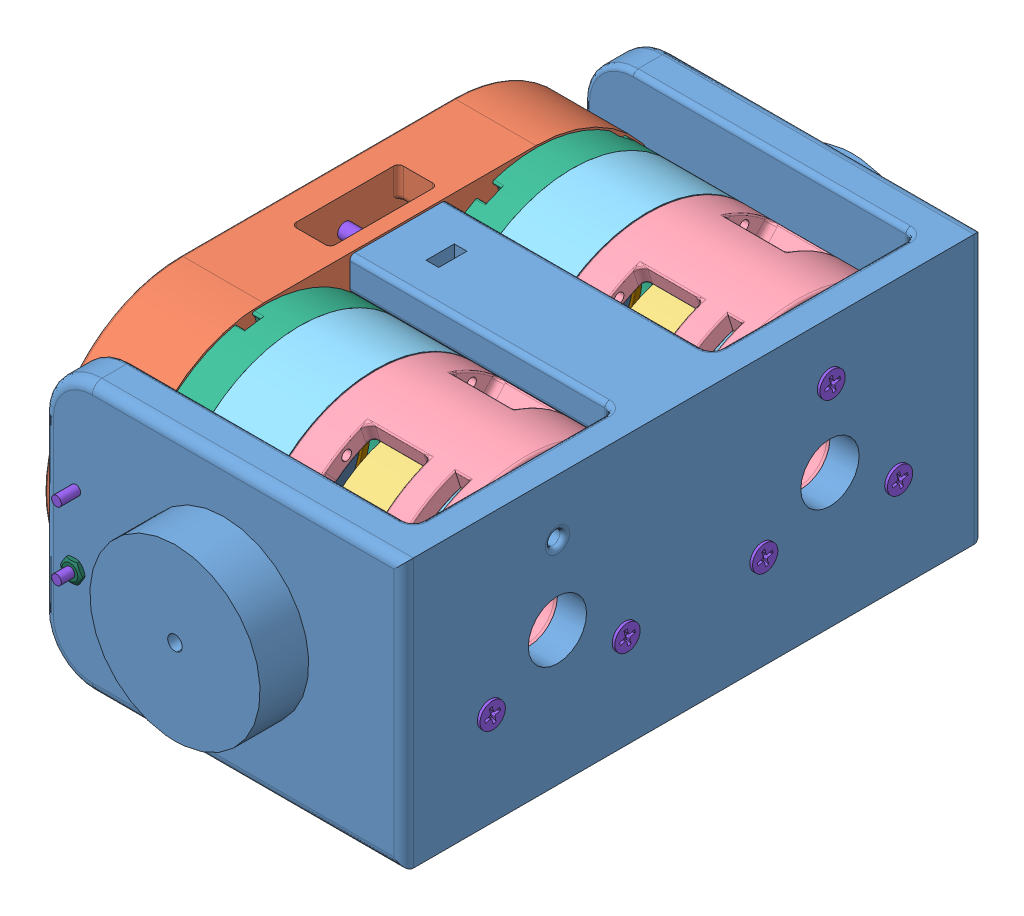
SolidWorks assembly LB_JIAN_LINK, configuration 默认. Lengths in mm.
Overall size (79.65 79.62 139.2).
41 component instances, 17 part files, 83 mates.
Components (placement in the parent):
- 支撑架-1: 支撑架 [默认] at (-17 -1 93.9) x (0 0 -1) z (0 -1 0) size (139.2 74 55.2)
- 保持架-1: 保持架 [默认] at (-87.4 -1 121.9) x (0 0 -1) z (0 -1 0) size (112 17 56)
- 电机46-1: 电机46 [默认] at (-28.3 -1 65.9) x (0 0.5 0.866025) z (0 -0.866025 0.5) size (46 26.5 46)
- 电机46-2: 电机46 [默认] at (-28.3 -1 121.9) x (0 0.5 0.866025) z (0 -0.866025 0.5) size (46 26.5 46)
- 电机座-1: 电机座 [默认] at (-48.5 -1 65.9) x (0 1 0) z (1 0 0) size (55.2 55.2 31.5)
- 减速器壳体-1: 减速器壳体 [默认] at (-55 -1 65.9) x (0 0.95809 -0.286467) z (-1 0 0) size (55.2 55.2 15.5)
- 减速器上盖-1: 减速器上盖 [默认] at (-69.5 -1 65.9) x (0 -0.382558 0.923932) z (1 0 0) size (55.2 55.2 7.4)
- 电机座-2: 电机座 [默认] at (-48.5 -1 121.9) x (0 1 0) z (1 0 0) size (55.2 55.2 31.5)
- 减速器壳体-2: 减速器壳体 [默认] at (-55 -1 121.9) x (0 0.95809 -0.286467) z (-1 0 0) size (55.2 55.2 15.5)
- 减速器上盖-2: 减速器上盖 [默认] at (-69.5 -1 121.9) x (0 -0.142607 0.989779) z (1 0 0) size (55.2 55.2 7.4)
- 111-1: 111 [GearTrax] at (-82.6296 -1 65.9) x (0 -0.999993 -0.00364) z (-1 0 0) size (36 36 12)
- cross recessed countersunk head screws gb1-1: cross recessed countersunk head screws gb1 [GB_CROSS_SCREWS_TYPE4 M3X30-28.35  H type-N] at (-88.4 20.6 94.1763) x (1 0 0) z (0 0.381849 -0.924225) size (30 5.2 5.2)
- cross recessed countersunk head screws gb1-2: cross recessed countersunk head screws gb1 [GB_CROSS_SCREWS_TYPE4 M2X10-8.8  H type-N] at (-80.85 -1.0364 75.8999) x (1 0 0) z (0 0.319354 -0.947635) size (10 3.5 3.5)
- cross recessed countersunk head screws gb1-3: cross recessed countersunk head screws gb1 [GB_CROSS_SCREWS_TYPE4 M2X10-8.8  H type-N] at (-80.85 7.6784 60.9316) x (1 0 0) z (0 -0.314861 0.949138) size (10 3.5 3.5)
- cross recessed countersunk head screws gb1-4: cross recessed countersunk head screws gb1 [GB_CROSS_SCREWS_TYPE4 M2X10-8.8  H type-N] at (-80.85 -9.642 60.8685) x (1 0 0) z (0 0.635086 -0.772442) size (10 3.5 3.5)
- 30-37-4轴承6-1: 30-37-4轴承6 [默认] at (-70 -1 65.9) x (0 -0.381849 0.924225) z (1 0 0) size (37 37 4)
- 输出轴-1: 输出轴 [默认] at (-66.4 -1 65.9) x (0 0.234884 -0.972023) z (-1 0 0) size (35 35 10)
- 输出轴-2: 输出轴 [默认] at (-66.4 -1 121.9) x (0 -0.166349 -0.986067) z (-1 0 0) size (35 35 10)
- 30-37-4轴承6-2: 30-37-4轴承6 [默认] at (-70 -1 121.9) x (0 -0.982984 -0.18369) z (1 0 0) size (37 37 4)
- 17-23-4轴承-1: 17-23-4轴承 [默认] at (-79.4 -1 121.9) x (0 0.928065 -0.372419) z (1 0 0) size (23 23 4)
- 35-44-5轴承-1: 35-44-5轴承 [默认] at (-82.4 -1 121.9) x (0 -0.705045 -0.709162) z (-1 0 0) size (44 44 5)
- 光杆同步轮10-1: 光杆同步轮10 [GearTrax] at (-77.4 -1 121.9) x (0 0.013702 0.999906) z (1 0 0) size (35.45 35.52 14.5)
- 张紧轮-1: 张紧轮 [默认] at (-74.4 -17.6 94.1763) x (0 -0.336964 0.941518) z (0 -0.941518 -0.336964) size (4.1 6.5 4.1)
- cross recessed countersunk head screws gb1-5: cross recessed countersunk head screws gb1 [GB_CROSS_SCREWS_TYPE4 M2X14-12.8  H type-N] at (-78.4 6 44.85) x (0 0 -1) z (0.537696 0.843139 0) size (14 3.5 3.5)
- cross recessed countersunk head screws gb1-6: cross recessed countersunk head screws gb1 [GB_CROSS_SCREWS_TYPE4 M2X14-12.8  H type-N] at (-78.4 -8 143.45) x (0 0 1) z (0.215578 0.976487 0) size (14 3.5 3.5)
- cross recessed countersunk head screws gb1-7: cross recessed countersunk head screws gb1 [GB_CROSS_SCREWS_TYPE4 M3X30-28.35  H type-N] at (-88.4 -22.6 94.1763) x (1 0 0) z (0 -0.924225 -0.381849) size (30 5.2 5.2)
- hex thin nuts-grades ab-chamfered gb-1: hex thin nuts-grades ab-chamfered gb [GB_FASTENER_NUT_STNAB M2-N] at (-78.4 -8 154.7) x (-1 0 0) z (0 0 1) size (4.62 4 1.2)
- hex thin nuts-grades ab-chamfered gb-2: hex thin nuts-grades ab-chamfered gb [GB_FASTENER_NUT_STNAB M2-N] at (-78.4 -8 33.1) x (-0.837169 0.546944 0) z (0 0 -1) size (4.62 4 1.2)
- hex thin nuts-grades ab-chamfered gb-3: hex thin nuts-grades ab-chamfered gb [GB_FASTENER_NUT_STNAB M2-N] at (-78.4 6 33.1) x (-0.837169 0.546944 0) z (0 0 -1) size (4.62 4 1.2)
- cross recessed countersunk head screws gb1-8: cross recessed countersunk head screws gb1 [GB_CROSS_SCREWS_TYPE4 M3X14-12.35  H type-N] at (-10.45 -9 135.7564) x (-1 0 0) z (0 0.967869 0.251457) size (14 5.2 5.2)
- cross recessed countersunk head screws gb1-9: cross recessed countersunk head screws gb1 [GB_CROSS_SCREWS_TYPE4 M3X14-12.35  H type-N] at (-10.45 -9 108.0436) x (-1 0 0) z (0 0.967869 0.251457) size (14 5.2 5.2)
- cross recessed countersunk head screws gb1-10: cross recessed countersunk head screws gb1 [GB_CROSS_SCREWS_TYPE4 M3X14-12.35  H type-N] at (-10.45 -9 79.7564) x (-1 0 0) z (0 0.967869 0.251457) size (14 5.2 5.2)
- cross recessed countersunk head screws gb1-11: cross recessed countersunk head screws gb1 [GB_CROSS_SCREWS_TYPE4 M3X14-12.35  H type-N] at (-10.45 15 65.9) x (-1 0 0) z (0 0.967869 0.251457) size (14 5.2 5.2)
- cross recessed countersunk head screws gb1-12: cross recessed countersunk head screws gb1 [GB_CROSS_SCREWS_TYPE4 M3X14-12.35  H type-N] at (-10.45 -9 52.0436) x (-1 0 0) z (0 0.967869 0.251457) size (14 5.2 5.2)
- hex nuts, style 1-grades ab gb-1: hex nuts, style 1-grades ab gb [GB_FASTENER_NUT_SNAB1 M3-N] at (-60.3 20.6 94.1763) x (0 -0.591684 0.80617) z (1 0 0) size (6.35 5.5 2.4)
- hex nuts, style 1-grades ab gb-2: hex nuts, style 1-grades ab gb [GB_FASTENER_NUT_SNAB1 M3-N] at (-60.3 -22.6 94.1763) x (0 -0.381849 0.924225) z (1 0 0) size (6.35 5.5 2.4)
- 同步带168-1: 同步带168 [默认] at (-82.4 -1 121.9) x (0 0.00364 -0.999993) z (0 -0.999993 -0.00364) size (93.52 7 37.52)
- cross recessed countersunk head screws gb1-13: cross recessed countersunk head screws gb1 [GB_CROSS_SCREWS_TYPE4 M2X14-12.8  H type-N] at (-78.4 6 143.45) x (0 0 1) z (0.215611 0.976479 0) size (14 3.5 3.5)
- cross recessed countersunk head screws gb1-14: cross recessed countersunk head screws gb1 [GB_CROSS_SCREWS_TYPE4 M2X16-14.8  H type-N] at (-85.85 -17.6 94.1763) x (1 0 0) z (0 0.420598 0.907247) size (16 3.5 3.5)
- hex nuts, style 1-grades ab gb-3: hex nuts, style 1-grades ab gb [GB_FASTENER_NUT_SNAB1 M2-N] at (-59.3578 -17.6 94.1763) x (0 0.881074 0.472978) z (1 0 0) size (4.62 4 1.6)
- hex nuts, style 1-grades ab gb-4: hex nuts, style 1-grades ab gb [GB_FASTENER_NUT_SNAB1 M2-N] at (-88.5 0.6895 96.8569) x (0 -0.895247 0.44557) z (1 0 0) size (4.62 4 1.6)
Mates (geometry in assembly coordinates):
- 平行3: parallel aligned: plane of 保持架-1 through (-82.4 -29 121.9) normal (0 -1 0); plane of 支撑架-1 through (-11 -28.6 38.3) normal (0 -1 0)
- 重合284: coincident anti-aligned: plane of 电机座-1 through (-48.5 -1 65.9) normal (0 1 0); plane of 保持架-1 through (-87.4 -1 121.9) normal (0 -1 0)
- 同心547: concentric anti-aligned: cylinder of 电机座-1 through (-20.5 -1 65.9) axis (-1 0 0) radius 23.75; cylinder of 电机46-1 through (-29.3 -1 65.9) axis (1 0 0) radius 23
- 重合294: coincident anti-aligned: plane of 电机座-1 through (-20.5 -1 65.9) normal (-1 0 0); plane of 电机46-1 through (-20.5 4.24 48.0984) normal (1 0 0)
- 同心548: concentric anti-aligned: cylinder of 电机座-1 through (-48.5 -14.8564 57.9) axis (1 0 0) radius 1.5; cylinder of 电机46-1 through (-28.3 -14.8564 57.9) axis (-1 0 0) radius 1.25
- 同心552: concentric anti-aligned: cylinder of 电机座-1 through (-20.5 -1 65.9) axis (-1 0 0) radius 27.6; cylinder of 减速器壳体-1 through (-64 -1 65.9) axis (1 0 0) radius 27.6
- 重合297: coincident anti-aligned: plane of 电机座-1 through (-48.5 -1 65.9) normal (-1 0 0); plane of 减速器壳体-1 through (-48.5 -1 65.9) normal (1 0 0)
- 同心553: concentric anti-aligned: cylinder of 减速器壳体-1 through (-64 -1 65.9) axis (1 0 0) radius 27.6; cylinder of 减速器上盖-1 through (-64 -1 65.9) axis (-1 0 0) radius 27.6
- 重合300: coincident anti-aligned: plane of 减速器壳体-1 through (-64 -1 65.9) normal (-1 0 0); plane of 减速器上盖-1 through (-64 -1 65.9) normal (1 0 0)
- 重合263: coincident anti-aligned: plane of 电机座-2 through (-17 -1 121.9) normal (1 0 0); plane of 支撑架-1 through (-17 -1 93.9) normal (-1 0 0)
- 同心533: concentric anti-aligned: cylinder of 电机座-2 through (-20.5 -1 121.9) axis (-1 0 0) radius 27.6; cylinder of 支撑架-1 through (-17 -1 121.9) axis (1 0 0) radius 6
- 同心549: concentric anti-aligned: cylinder of 电机座-2 through (-20.5 -1 121.9) axis (-1 0 0) radius 23.75; cylinder of 电机46-2 through (-29.3 -1 121.9) axis (1 0 0) radius 23
- 重合295: coincident anti-aligned: plane of 电机座-2 through (-20.5 -1 121.9) normal (-1 0 0); plane of 电机46-2 through (-20.5 4.24 104.0984) normal (1 0 0)
- 同心550: concentric anti-aligned: cylinder of 电机座-2 through (-48.5 -14.8564 113.9) axis (1 0 0) radius 1.5; cylinder of 电机46-2 through (-28.3 -14.8564 113.9) axis (-1 0 0) radius 1.25
- 重合298: coincident aligned: plane of 电机座-2 through (-48.5 -1 121.9) normal (0 1 0); plane of 电机座-1 through (-48.5 -1 65.9) normal (0 1 0)
- 重合299: coincident aligned: plane of 电机座-2 through (-17 -1 121.9) normal (1 0 0); plane of 电机座-1 through (-17 -1 65.9) normal (1 0 0)
- 距离48: distance = 56 mm aligned: plane of 电机座-1 through (-48.5 -1 65.9) normal (0 0 1); plane of 电机座-2 through (-48.5 -1 121.9) normal (0 0 1)
- 同心556: concentric anti-aligned: cylinder of 电机座-2 through (-20.5 -1 121.9) axis (-1 0 0) radius 27.6; cylinder of 减速器壳体-2 through (-64 -1 121.9) axis (1 0 0) radius 27.6
- 重合302: coincident anti-aligned: plane of 电机座-2 through (-48.5 -1 121.9) normal (-1 0 0); plane of 减速器壳体-2 through (-48.5 -1 121.9) normal (1 0 0)
- 重合285: coincident anti-aligned: plane of 减速器上盖-2 through (-71.4 -1 121.9) normal (-1 0 0); plane of 保持架-1 through (-71.4 -1 121.9) normal (1 0 0)
- 同心557: concentric anti-aligned: cylinder of 减速器壳体-2 through (-64 -1 121.9) axis (1 0 0) radius 27.6; cylinder of 减速器上盖-2 through (-64 -1 121.9) axis (-1 0 0) radius 27.6
- 重合303: coincident anti-aligned: plane of 减速器壳体-2 through (-64 -1 121.9) normal (-1 0 0); plane of 减速器上盖-2 through (-64 -1 121.9) normal (1 0 0)
- 同心555: concentric aligned: cylinder of 减速器上盖-1 through (-64 -1 65.9) axis (-1 0 0) radius 27.6; cylinder of 111-1 through (-70.25 -1 65.9) axis (-1 0 0) radius 18
- 同心544: concentric anti-aligned: cylinder of 保持架-1 through (-67.2988 20.6 94.1763) axis (-1 0 0) radius 1.45; cylinder of cross recessed countersunk head screws gb1-1 through (-83.8842 20.6 94.1763) axis (1 0 0) radius 1.5
- 重合289: coincident aligned: plane of 保持架-1 through (-88.4 -1 121.9) normal (-1 0 0); plane of cross recessed countersunk head screws gb1-1 through (-88.4 18.197 93.1835) normal (-1 0 0)
- 同心565: concentric aligned: cylinder of 111-1 through (-85.4 -1.0364 75.8999) axis (1 0 0) radius 1; cylinder of cross recessed countersunk head screws gb1-2 through (-76.3342 -1.0364 75.8999) axis (1 0 0) radius 1
- 重合307: coincident anti-aligned: circle of 111-1; unknown of cross recessed countersunk head screws gb1-2
- 同心563: concentric aligned: cylinder of 111-1 through (-85.4 7.6784 60.9316) axis (1 0 0) radius 1; cylinder of cross recessed countersunk head screws gb1-3 through (-76.3342 7.6784 60.9316) axis (1 0 0) radius 1
- 重合306: coincident anti-aligned: plane of 111-1 through (-80.4 7.6784 60.9316) normal (-1 0 0); unknown of cross recessed countersunk head screws gb1-3
- 同心564: concentric aligned: cylinder of 111-1 through (-85.4 -9.642 60.8685) axis (1 0 0) radius 1; cylinder of cross recessed countersunk head screws gb1-4 through (-76.3342 -9.642 60.8685) axis (1 0 0) radius 1
- 重合308: coincident anti-aligned: plane of 111-1 through (-80.4 -9.642 60.8685) normal (-1 0 0); unknown of cross recessed countersunk head screws gb1-4
- 同心554: concentric aligned: cylinder of 减速器上盖-1 through (-66 -1 65.9) axis (-1 0 0) radius 18.5; cylinder of 30-37-4轴承6-1 through (-66 -1 65.9) axis (-1 0 0) radius 18.5
- 重合301: coincident anti-aligned: plane of 减速器上盖-1 through (-66 -1 65.9) normal (-1 0 0); plane of 30-37-4轴承6-1 through (-66 -1 65.9) normal (1 0 0)
- 重合305: coincident anti-aligned: plane of 输出轴-1 through (-71.4 -1 65.9) normal (-1 0 0); plane of 111-1 through (-71.4 -1 65.9) normal (1 0 0)
- 同心568: concentric aligned: cylinder of 输出轴-1 through (-23.9736 -1 65.9) axis (-1 0 0) radius 15; cylinder of 30-37-4轴承6-1 through (-66 -1 65.9) axis (-1 0 0) radius 15
- 重合310: coincident anti-aligned: plane of 输出轴-1 through (-70 -1 65.9) normal (1 0 0); plane of 30-37-4轴承6-1 through (-70 -1 65.9) normal (-1 0 0)
- 同心559: concentric aligned: cylinder of 减速器上盖-2 through (-66 -1 121.9) axis (-1 0 0) radius 18.5; cylinder of 30-37-4轴承6-2 through (-66 -1 121.9) axis (-1 0 0) radius 18.5
- 重合304: coincident anti-aligned: plane of 减速器上盖-2 through (-66 -1 121.9) normal (-1 0 0); plane of 30-37-4轴承6-2 through (-66 -1 121.9) normal (1 0 0)
- 同心569: concentric aligned: cylinder of 30-37-4轴承6-2 through (-66 -1 121.9) axis (-1 0 0) radius 15; cylinder of 输出轴-2 through (-23.9736 -1 121.9) axis (-1 0 0) radius 15
- 重合311: coincident anti-aligned: plane of 30-37-4轴承6-2 through (-70 -1 121.9) normal (-1 0 0); plane of 输出轴-2 through (-70 -1 121.9) normal (1 0 0)
- 同心542: concentric anti-aligned: cylinder of 35-44-5轴承-1 through (-87.4 -1 121.9) axis (1 0 0) radius 22; cylinder of 保持架-1 through (-82.4 -1 121.9) axis (-1 0 0) radius 22
- 重合286: coincident anti-aligned: plane of 35-44-5轴承-1 through (-87.4 -1 121.9) normal (-1 0 0); plane of 保持架-1 through (-87.4 -1 121.9) normal (1 0 0)
- 平行32: parallel anti-aligned: cylinder of 减速器上盖-2 through (-64 -1 121.9) axis (-1 0 0) radius 27.6; cylinder of 35-44-5轴承-1 through (-87.4 -1 121.9) axis (1 0 0) radius 17.5
- 同心562: concentric anti-aligned: cylinder of 减速器上盖-2 through (-64 -1 121.9) axis (-1 0 0) radius 27.6; cylinder of 35-44-5轴承-1 through (-87.4 -1 121.9) axis (1 0 0) radius 17.5
- 同心558: concentric aligned: cylinder of 减速器壳体-2 through (-64 -1 121.9) axis (1 0 0) radius 27.6; cylinder of 光杆同步轮10-1 through (-82.4 -1 121.9) axis (1 0 0) radius 11.5
- 同心561: concentric anti-aligned: cylinder of 减速器上盖-2 through (-64 -1 121.9) axis (-1 0 0) radius 27.6; cylinder of 光杆同步轮10-1 through (-82.4 -1 121.9) axis (1 0 0) radius 11.5
- 同心592: concentric anti-aligned: cylinder of 光杆同步轮10-1 through (-82.4 -1 121.9) axis (1 0 0) radius 11.5; cylinder of 17-23-4轴承-1 through (-75.4 -1 121.9) axis (-1 0 0) radius 8.5
- 重合328: coincident anti-aligned: plane of 光杆同步轮10-1 through (-82.4 17.7554 103.9174) normal (-1 0 0); plane of 35-44-5轴承-1 through (-82.4 -1 121.9) normal (1 0 0)
- 重合287: coincident anti-aligned: plane of 保持架-1 through (-74.4 -1 121.9) normal (-1 0 0); plane of 张紧轮-1 through (-74.4 -17.6 94.1763) normal (1 0 0)
- 同心534: concentric aligned: cylinder of 支撑架-1 through (-78.4 6 163.5) axis (0 0 -1) radius 1; cylinder of cross recessed countersunk head screws gb1-5 through (-78.4 6 40.3342) axis (0 0 -1) radius 1
- 重合291: coincident anti-aligned: plane of 保持架-1 through (-82.4 -1 44.4) normal (0 0 1); unknown of cross recessed countersunk head screws gb1-5
- 同心535: concentric anti-aligned: cylinder of 支撑架-1 through (-78.4 -8 163.5) axis (0 0 -1) radius 1; cylinder of cross recessed countersunk head screws gb1-6 through (-78.4 -8 147.9658) axis (0 0 1) radius 1
- 重合290: coincident anti-aligned: plane of 保持架-1 through (-83.4 -1 143.9) normal (0 0 -1); unknown of cross recessed countersunk head screws gb1-6
- 同心543: concentric anti-aligned: cylinder of 保持架-1 through (-67.2988 -22.6 94.1763) axis (-1 0 0) radius 1.45; cylinder of cross recessed countersunk head screws gb1-7 through (-83.8842 -22.6 94.1763) axis (1 0 0) radius 1.5
- 重合288: coincident aligned: plane of 保持架-1 through (-88.4 -1 121.9) normal (-1 0 0); plane of cross recessed countersunk head screws gb1-7 through (-88.4 -23.5928 96.5793) normal (-1 0 0)
- 重合379: coincident anti-aligned: plane of 支撑架-1 through (-85 26.6 153.5) normal (0 0 1); plane of hex thin nuts-grades ab-chamfered gb-1 through (-77.2453 -6 153.5) normal (0 0 -1)
- 同心657: concentric aligned: cylinder of cross recessed countersunk head screws gb1-6 through (-78.4 -8 147.9658) axis (0 0 1) radius 1; cylinder of hex thin nuts-grades ab-chamfered gb-1 through (-78.4 -8 153.5) axis (0 0 1) radius 0.7835
- 重合265: coincident anti-aligned: plane of 支撑架-1 through (-85 26.6 34.3) normal (0 0 -1); plane of hex thin nuts-grades ab-chamfered gb-2 through (-78.5272 -10.3059 34.3) normal (0 0 1)
- 重合266: coincident anti-aligned: plane of 支撑架-1 through (-85 26.6 34.3) normal (0 0 -1); plane of hex thin nuts-grades ab-chamfered gb-3 through (-78.5272 3.6941 34.3) normal (0 0 1)
- 同心653: concentric aligned: cylinder of cross recessed countersunk head screws gb1-5 through (-78.4 6 40.3342) axis (0 0 -1) radius 1; unknown of hex thin nuts-grades ab-chamfered gb-3
- 重合271: coincident anti-aligned: cylinder of 支撑架-1; cylinder of cross recessed countersunk head screws gb1-8 through (-14.9658 -9 135.7564) axis (-1 0 0) radius 1.5
- 重合272: coincident anti-aligned: plane of 支撑架-1 through (-11 -1 93.9) normal (1 0 0); unknown of cross recessed countersunk head screws gb1-8
- 重合270: coincident anti-aligned: cylinder of 支撑架-1; cylinder of cross recessed countersunk head screws gb1-9 through (-14.9658 -9 108.0436) axis (-1 0 0) radius 1.5
- 重合274: coincident anti-aligned: plane of 支撑架-1 through (-11 -1 93.9) normal (1 0 0); unknown of cross recessed countersunk head screws gb1-9
- 同心537: concentric anti-aligned: cylinder of 支撑架-1 through (-17 -9 79.7564) axis (1 0 0) radius 1.5; cylinder of cross recessed countersunk head screws gb1-10 through (-14.9658 -9 79.7564) axis (-1 0 0) radius 1.5
- 重合277: coincident anti-aligned: plane of 支撑架-1 through (-11 -1 93.9) normal (1 0 0); unknown of cross recessed countersunk head screws gb1-10
- 重合268: coincident anti-aligned: cylinder of 支撑架-1; cylinder of cross recessed countersunk head screws gb1-11 through (-14.9658 15 65.9) axis (-1 0 0) radius 1.5
- 重合276: coincident anti-aligned: plane of 支撑架-1 through (-11 -1 93.9) normal (1 0 0); unknown of cross recessed countersunk head screws gb1-11
- 同心536: concentric anti-aligned: cylinder of 支撑架-1 through (-17 -9 52.0436) axis (1 0 0) radius 1.5; cylinder of cross recessed countersunk head screws gb1-12 through (-14.9658 -9 52.0436) axis (-1 0 0) radius 1.5
- 重合275: coincident anti-aligned: plane of 支撑架-1 through (-11 -1 93.9) normal (1 0 0); unknown of cross recessed countersunk head screws gb1-12
- 重合278: coincident anti-aligned: plane of 支撑架-1 through (-62.7 16.6 97.1977) normal (1 0 0); plane of hex nuts, style 1-grades ab gb-1 through (-62.7 18.7212 96.7362) normal (-1 0 0)
- 同心566: concentric aligned: cylinder of cross recessed countersunk head screws gb1-1 through (-83.8842 20.6 94.1763) axis (1 0 0) radius 1.5; cylinder of hex nuts, style 1-grades ab gb-1 through (-62.7 20.6 94.1763) axis (1 0 0) radius 1.2295
- 重合279: coincident anti-aligned: plane of 支撑架-1 through (-62.7 -18.6 97.1977) normal (1 0 0); plane of hex nuts, style 1-grades ab gb-2 through (-62.7 -23.8125 97.1111) normal (-1 0 0)
- 同心656: concentric aligned: cylinder of cross recessed countersunk head screws gb1-7 through (-83.8842 -22.6 94.1763) axis (1 0 0) radius 1.5; cylinder of hex nuts, style 1-grades ab gb-2 through (-62.7 -22.6 94.1763) axis (1 0 0) radius 1.2295
- 平行33: parallel aligned: plane of 111-1 through (-82.6296 -1 65.9) normal (0 -0.999993 -0.00364); plane of 同步带168-1 through (-75.4 -19.7599 121.8317) normal (0 -0.999993 -0.00364)
- 同心635: concentric aligned: cylinder of 光杆同步轮10-1 through (-79.4 -1 121.9) axis (-1 0 0) radius 9.5; cylinder of 同步带168-1 through (-75.4 -1 121.9) axis (-1 0 0) radius 16.76
- 重合362: coincident anti-aligned: plane of 光杆同步轮10-1 through (-82.4 -1 121.9) normal (1 0 0); plane of 同步带168-1 through (-82.4 -1 121.9) normal (-1 0 0)
- 同心545: concentric anti-aligned: cylinder of 保持架-1 through (-78.4 6 149.9) axis (0 0 -1) radius 1; cylinder of cross recessed countersunk head screws gb1-13 through (-78.4 6 147.9658) axis (0 0 1) radius 1
- 重合376: coincident aligned: plane of cross recessed countersunk head screws gb1-6 through (-77.4235 -8.2156 157.45) normal (0 0 1); plane of cross recessed countersunk head screws gb1-13 through (-77.4235 5.7844 157.45) normal (0 0 1)
- 重合293: coincident anti-aligned: plane of 保持架-1 through (-85.4 -17.6 94.1763) normal (-1 0 0); unknown of cross recessed countersunk head screws gb1-14
- 同心546: concentric anti-aligned: cylinder of 保持架-1 through (-85.4 -17.6 94.1763) axis (-1 0 0) radius 2.25; cylinder of cross recessed countersunk head screws gb1-14 through (-81.3342 -17.6 94.1763) axis (1 0 0) radius 1
- 同心651: concentric aligned: cylinder of 张紧轮-1 through (-81.9 -17.6 94.1763) axis (1 0 0) radius 1.05; cylinder of cross recessed countersunk head screws gb1-14 through (-81.3342 -17.6 94.1763) axis (1 0 0) radius 1
- 同心659: concentric aligned: cylinder of cross recessed countersunk head screws gb1-14 through (-81.3342 -17.6 94.1763) axis (1 0 0) radius 1; cylinder of hex nuts, style 1-grades ab gb-3 through (-60.9578 -17.6 94.1763) axis (1 0 0) radius 0.7835
